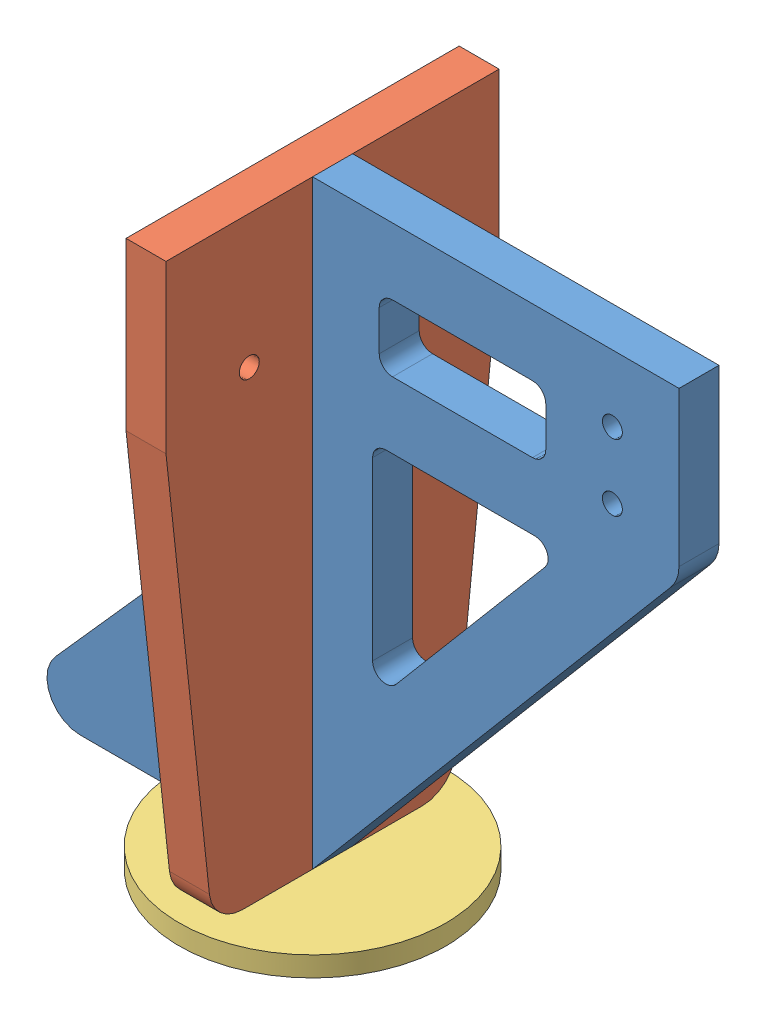
SolidWorks assembly SUBASSY_landinggear, configuration Default. Lengths in mm.
Overall size (94.87 93 50).
3 component instances, 3 part files, 6 mates.
Components (placement in the parent):
- LDG_GEAR_E_mal_2-1: LDG_GEAR_E_mal_2 [Default] at (14.5914 90.1956 64.2515) size (94.87 90 6)
- LDG_GEAR_E_FEM_2-1: LDG_GEAR_E_FEM_2 [Default] at (8.5914 90.1956 67.2515) x (0 0 -1) z (1 0 0) size (50 90 6)
- landinggear_pad-1: landinggear_pad [Default] at (11.5914 0.1956 67.2515) x (1 0 0) z (0 -1 0) size (40 40 3)
Mates (geometry in assembly coordinates):
- Coincident1: coincident anti-aligned: plane of LDG_GEAR_E_mal_2-1 through (14.5914 90.1956 70.2515) normal (-1 0 0); plane of LDG_GEAR_E_FEM_2-1 through (14.5914 90.1956 67.2515) normal (1 0 0)
- Coincident2: coincident anti-aligned: plane of LDG_GEAR_E_mal_2-1 through (14.5914 45.1956 70.2515) normal (0 1 0); plane of LDG_GEAR_E_FEM_2-1 through (8.5914 45.1956 70.2515) normal (0 -1 0)
- Coincident3: coincident anti-aligned: plane of LDG_GEAR_E_mal_2-1 through (14.5914 90.1956 70.2515) normal (0 0 1); plane of LDG_GEAR_E_FEM_2-1 through (8.5914 45.1956 70.2515) normal (0 0 -1)
- Coincident4: coincident: point of landinggear_pad-1; point of assembly
- Parallel1: parallel anti-aligned: plane of landinggear_pad-1 through (11.5914 0.1956 67.2515) normal (0 1 0); plane of LDG_GEAR_E_mal_2-1 through (-31.4086 0.1956 70.2515) normal (0 -1 0)
- Parallel2: parallel aligned: plane of landinggear_pad-1 through (11.5914 0.1956 67.2515) normal (1 0 0)
